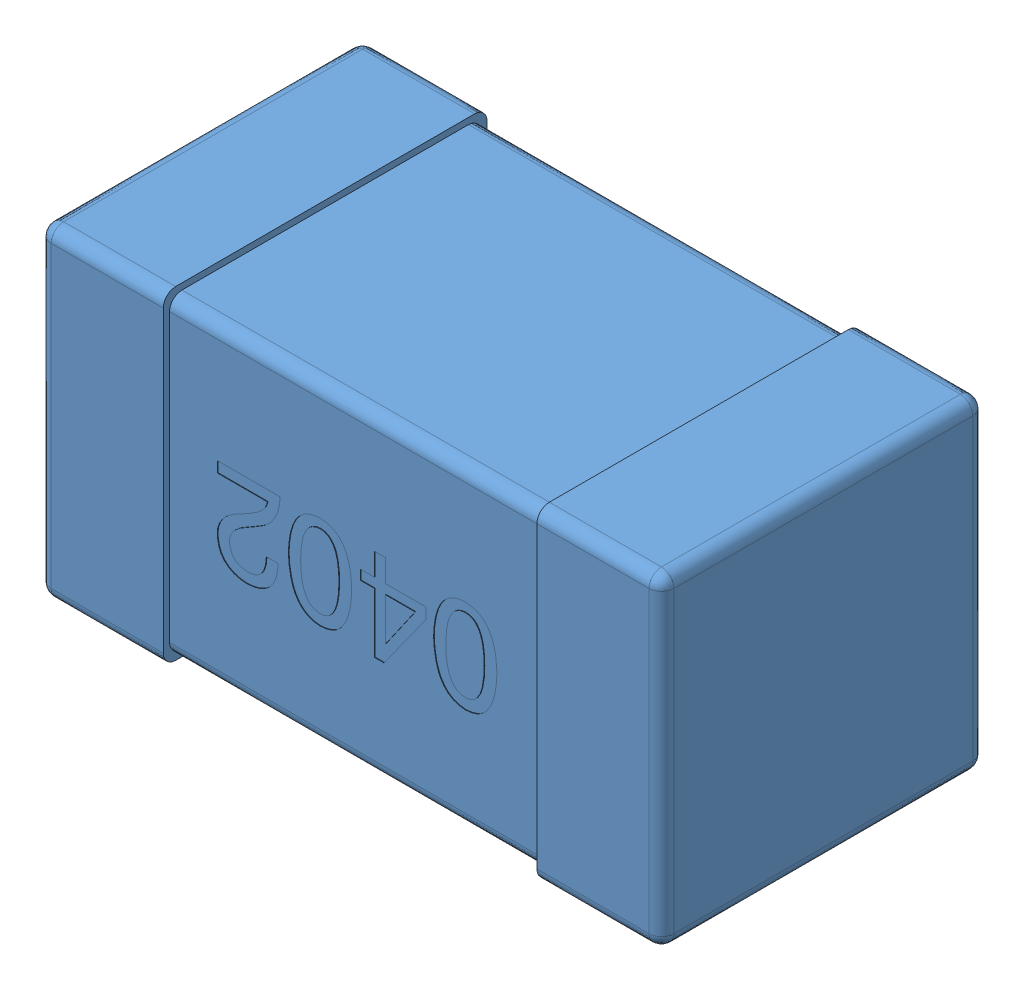
SolidWorks assembly 0402电容, configuration 默认. Lengths in mm.
Overall size (1 0.52 0.52).
2 component instances, 1 part files, 0 mates.
Components (placement in the parent):
- C_0402^0402电容-1: C_0402^0402电容 [默认] at (34.005 41.148 0.0152) x (-1 0 0) z (0 0 1) size (1 0.52 0.52) (virtual)
  - C_0402-7^C_0402_0402电容-1: C_0402-7^C_0402_0402电容 [默认] at origin size (1 0.52 0.52) (virtual)
